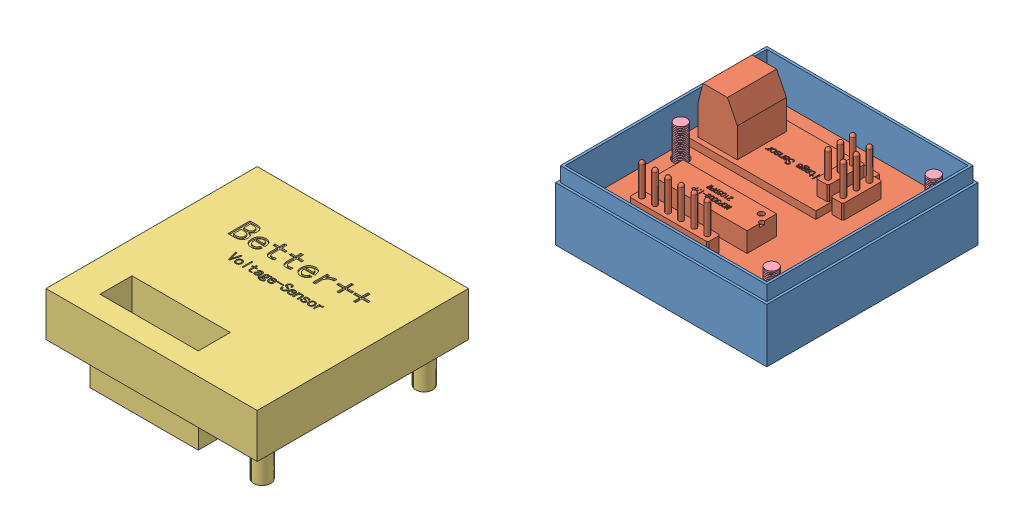
SolidWorks assembly 装配体-电压表, configuration 默认. Lengths in mm.
Overall size (67.18 21.03 122.54).
6 component instances, 4 part files, 16 mates.
Components (placement in the parent):
- 下底外壳-1: 下底外壳 [默认] at (7.6597 -8.7437 39.0714) size (43 14 43)
- 电压表原件-1: 电压表原件 [默认] at (2.1506 -3.7437 43) x (-1 0 0) z (0 0 -1) size (40.73 13 40)
- 电压表上底壳-1: 电压表上底壳 [默认] at (-22.028 11.2563 122.5407) x (1 0 0) z (0 0 -1) size (43 16.5 43)
- 螺丝头-1: 螺丝头 [默认] at (19.6506 -9.4807 59.5) x (0.33605 0 -0.941844) z (0.941844 0 0.33605) size (3.4 14.02 3.4)
- 螺丝头-2: 螺丝头 [默认] at (-15.3494 -9.7733 43) x (0.334618 0 -0.942354) z (0.942354 0 0.334618) size (3.4 14.02 3.4)
- 螺丝头-4: 螺丝头 [默认] at (19.6506 -9.7596 26.5) x (-0.2154 0 -0.976526) z (0.976526 0 -0.2154) size (3.4 14.02 3.4)
Mates (geometry in assembly coordinates):
- 平行1: parallel aligned: plane of 下底外壳-1 through (7.6597 -7.7437 39.0714) normal (0 1 0); plane of 电压表原件-1 through (2.1506 -2.2437 43) normal (0 1 0)
- 平行3: parallel anti-aligned: plane of 下底外壳-1 through (7.6597 -7.7437 39.0714) normal (0 1 0); plane of 电压表原件-1 through (2.1506 -3.7437 43) normal (0 -1 0)
- 同心1: concentric aligned: cylinder of 下底外壳-1 through (-15.3494 0.2563 43) axis (0 -1 0) radius 1.25; cylinder of 电压表原件-1 through (-15.3494 8.6566 43) axis (0 -1 0) radius 1.5
- 同心2: concentric anti-aligned: cylinder of 电压表原件-1 through (19.6506 -4.3444 59.5) axis (0 1 0) radius 1.5; cylinder of 下底外壳-1 through (19.6506 0.2563 59.5) axis (0 -1 0) radius 1.25
- 平行4: parallel anti-aligned: plane of 电压表原件-1 through (2.1506 -2.2437 43) normal (0 1 0); plane of 电压表上底壳-1 through (-22.028 10.2563 122.5407) normal (0 -1 0)
- 同心3: concentric anti-aligned: cylinder of 下底外壳-1 through (19.6506 0.2563 59.5) axis (0 -1 0) radius 1.25; cylinder of 电压表上底壳-1 through (19.6506 -5.2414 59.5) axis (0 1 0) radius 1.35
- 同心4: concentric anti-aligned: cylinder of 下底外壳-1 through (19.6506 0.2563 26.5) axis (0 -1 0) radius 1.25; cylinder of 电压表上底壳-1 through (19.6506 -5.2414 26.5) axis (0 1 0) radius 1.35
- 同心5: concentric anti-aligned: cylinder of 下底外壳-1 through (-15.3494 0.2563 43) axis (0 -1 0) radius 1.25; cylinder of 电压表上底壳-1 through (-15.3494 -5.2414 43) axis (0 1 0) radius 1.75
- 同心6: concentric aligned: cylinder of 下底外壳-1 through (19.6506 -8.7437 59.5) axis (0 1 0) radius 1.3; cylinder of 电压表原件-1 through (19.6506 -3.7437 59.5) axis (0 1 0) radius 1.5
- 同心7: concentric aligned: cylinder of 下底外壳-1 through (-15.3494 -8.7437 43) axis (0 1 0) radius 1.3; circle of 电压表原件-1
- 重合1: coincident anti-aligned: plane of 下底外壳-1 through (-15.3494 -3.7437 43) normal (0 1 0); plane of 电压表原件-1 through (2.1506 -3.7437 43) normal (0 -1 0)
- 重合2: coincident anti-aligned: plane of 下底外壳-1 through (7.6597 2.2563 39.0714) normal (0 1 0); plane of 电压表上底壳-1 through (-22.028 2.2563 122.5407) normal (0 -1 0)
- 同心8: concentric anti-aligned: circle of 下底外壳-1; cylinder of 螺丝头-2 through (-15.3494 -5.7733 43) axis (0 -1 0) radius 1.7
- 同心9: concentric aligned: cylinder of 螺丝头-2 through (-15.3494 -5.7733 43) axis (0 -1 0) radius 1.7; cylinder of 下底外壳-1 through (-15.3494 -5.7437 43) axis (0 -1 0) radius 1.55
- 同心10: concentric aligned: cylinder of 下底外壳-1 through (19.6506 -5.7437 59.5) axis (0 -1 0) radius 1.55; cylinder of 螺丝头-1 through (19.6506 -5.4807 59.5) axis (0 -1 0) radius 1.7
- 同心11: concentric aligned: cylinder of 下底外壳-1 through (19.6506 -5.7437 26.5) axis (0 -1 0) radius 1.55; cylinder of 螺丝头-4 through (19.6506 -5.7596 26.5) axis (0 -1 0) radius 1.7
